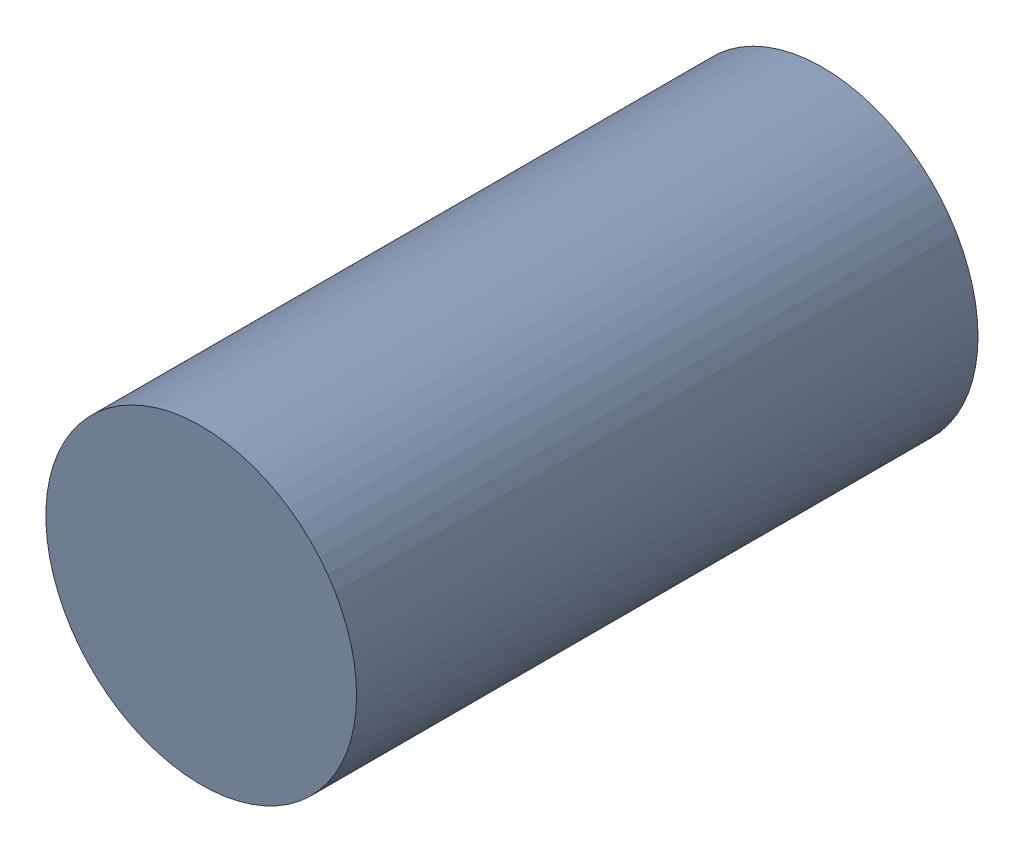
SolidWorks assembly MH7_1.step, configuration Default. Lengths in mm.
Overall size (1 1 2).
2 component instances, 1 part files, 0 mates.
Components (placement in the parent):
- 9228463120_1.step-3: 9228463120_1.step [Default] at (369.9996 241.0004 -1.5) size (1 1 2)
  - Cylinder_1.step-26: Cylinder_1.step [Default] at origin size (1 1 2)
